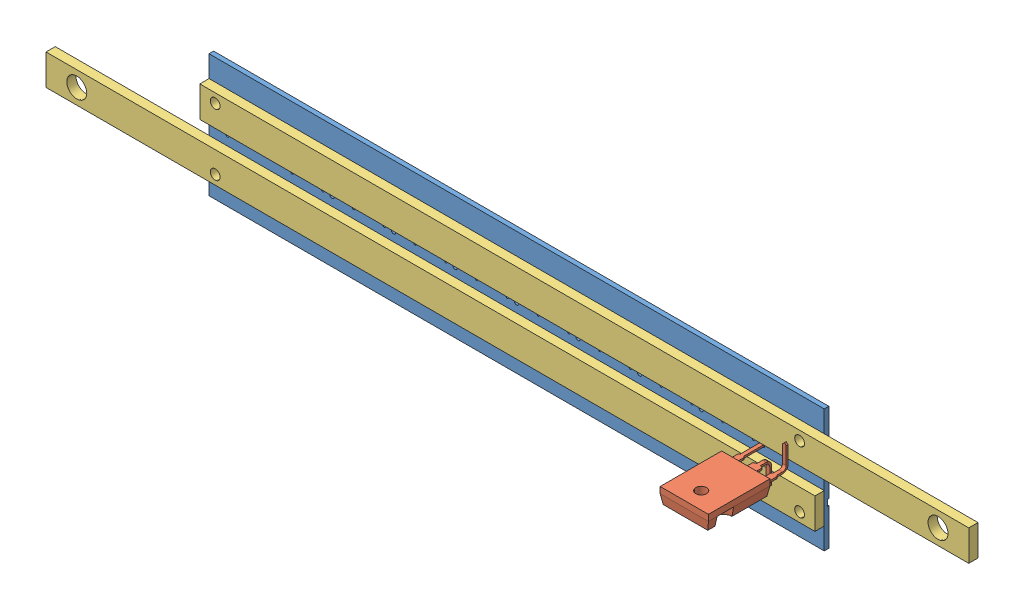
SolidWorks assembly Baugruppe Platine, configuration Standard. Lengths in mm.
Overall size (300 40 34.5).
4 component instances, 3 part files, 10 mates.
Components (placement in the parent):
- platine Mosfet-1: platine Mosfet [Standard] at origin size (200 40 1.5)
- Mosfet-1: Mosfet [Standard] at (85.3104 -2.71 21.55) x (1 0 0) z (0 1 0) size (15.7 34.5 15.29)
- Kupfer-1: Kupfer [Standard] at (25 8 2.25) x (0 1 0) z (1 0 0) size (10 3 250)
- Kupfer-2: Kupfer [Standard] at (-25 -8 2.25) x (0 -1 0) z (-1 0 0) size (10 3 250)
Mates (geometry in assembly coordinates):
- Deckungsgleich1: coincident anti-aligned: plane of platine Mosfet-1 through (0 0 0.75) normal (0 0 1); plane of Kupfer-1 through (150 3 0.75) normal (0 0 -1)
- Parallel1: parallel anti-aligned: plane of platine Mosfet-1 through (-100 -20 0.75) normal (0 -1 0); plane of Kupfer-1 through (150 13 3.75) normal (0 1 0)
- Konzentrisch1: concentric aligned: circle of platine Mosfet-1; circle of Kupfer-1
- Deckungsgleich4: coincident anti-aligned: plane of platine Mosfet-1 through (0 0 0.75) normal (0 0 1); plane of Kupfer-2 through (-150 -3 0.75) normal (0 0 -1)
- Parallel2: parallel anti-aligned: plane of platine Mosfet-1 through (-100 -20 0.75) normal (0 -1 0); plane of Kupfer-2 through (-150 -3 3.75) normal (0 1 0)
- Konzentrisch2: concentric aligned: circle of platine Mosfet-1; circle of Kupfer-2
- Deckungsgleich7: coincident anti-aligned: plane of Mosfet-1 through (85.9104 -1.51 3.75) normal (0 0 -1); plane of Kupfer-1 through (150 3 3.75) normal (0 0 1)
- Parallel3: parallel aligned: plane of Mosfet-1 through (85.3104 -2.71 21.55) normal (0 -1 0); plane of Kupfer-2 through (-150 -13 3.75) normal (0 -1 0)
- Abstand2: distance = 6.4 mm: moEndPointRef_w of Mosfet-1; line of platine Mosfet-1 through (100 6 -0.75) axis (-1 0 0)
- Abstand3: distance = 3 mm: moEndPointRef_w of Mosfet-1; line of platine Mosfet-1 through (82 2 -0.75) axis (0 -1 0)
